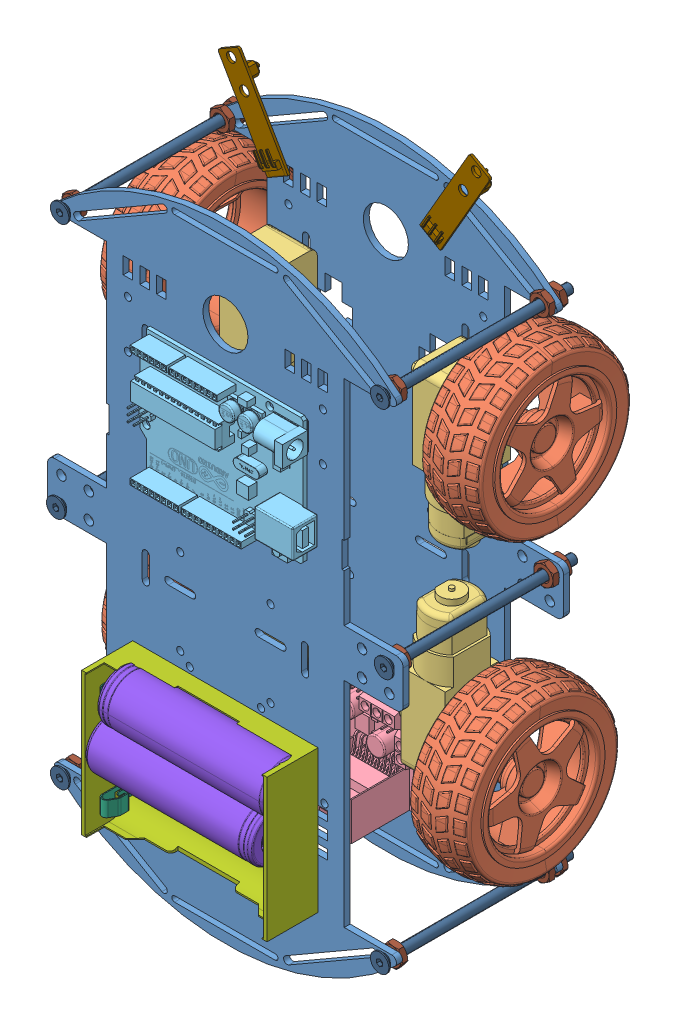
SolidWorks assembly Assem1, configuration Default. Lengths in mm.
Overall size (160.5 272.74 118.28).
52 component instances, 11 part files, 84 mates.
Components (placement in the parent):
- Chassis-1: Chassis [Défaut] at (34.1523 63.1715 225.3046) size (149.66 262 2.5)
- ensemble roue-1: ensemble roue [Default] at (48.6677 124.5638 247.2809) x (0 0.999098 -0.042468) z (-1 0 0) size (89.53 69.08 58.2)
  - Wheel D65x25-1: Wheel D65x25 [Default] at (-64.7956 10.9879 41.7655) size (69.1 69.08 30)
  - Arduino Gear Motor-1: Arduino Gear Motor [Default] at (-75.7856 11.455 2.1655) x (0 0 1) z (-0.999098 0.042468 0) size (37.2 22.5 65.5)
- ensemble roue-2: ensemble roue [Default] at (120.1368 124.5638 230.8284) x (0 0.999098 0.042468) z (1 0 0) size (89.53 69.08 58.2)
  - Wheel D65x25-1: Wheel D65x25 [Default] at (-64.7956 10.9879 41.7655) size (69.1 69.08 30)
  - Arduino Gear Motor-1: Arduino Gear Motor [Default] at (-75.7856 11.455 2.1655) x (0 0 1) z (-0.999098 0.042468 0) size (37.2 22.5 65.5)
- ensemble roue-4: ensemble roue [Default] at (48.1677 122.1564 230.8284) x (0 -0.999098 0.042468) z (-1 0 0) size (89.53 69.08 58.2)
  - Wheel D65x25-1: Wheel D65x25 [Default] at (-64.7956 10.9879 41.7655) size (69.1 69.08 30)
  - Arduino Gear Motor-1: Arduino Gear Motor [Default] at (-75.7856 11.455 2.1655) x (0 0 1) z (-0.999098 0.042468 0) size (37.2 22.5 65.5)
- ensemble roue-5: ensemble roue [Default] at (125.1368 122.1564 247.2809) x (0 -0.999098 -0.042468) z (1 0 0) size (89.53 69.08 58.2)
  - Wheel D65x25-1: Wheel D65x25 [Default] at (-64.7956 10.9879 41.7655) size (69.1 69.08 30)
  - Arduino Gear Motor-1: Arduino Gear Motor [Default] at (-75.7856 11.455 2.1655) x (0 0 1) z (-0.999098 0.042468 0) size (37.2 22.5 65.5)
- L298N Motor Driver-1: L298N Motor Driver [Default] at (84.1523 35.5001 227.8046) x (1 0 0) z (0 -1 0) size (43.5 26 43.5)
- Chassis-2: Chassis [Défaut] at (34.1523 63.1715 292.8046) size (149.66 262 2.5)
- Arduino UNO-1: Arduino UNO [Predeterminado] at (82.8616 175.6554 295.3046) x (-1 0 0) z (0 1 0) size (74.8 15.1 53.3)
- Hold_18650-3p.stp-1: Hold_18650-3p.stp [Default] at (84.1523 53.3601 295.3046) x (0 -1 0) z (0 0 1) size (60 78 25.5)
  - eBom-prt0.stp-1: eBom-prt0.stp [Default] at (-20 -36 0) size (6.4 5.3 21.4)
  - eBom-prt0.stp-2: eBom-prt0.stp [Default] at (-20 36 0) x (-1 0 0) z (0 0 1) size (6.4 5.3 21.4)
  - eBom-prt0.stp-3: eBom-prt0.stp [Default] at (0 -36 0) size (6.4 5.3 21.4)
  - eBom-prt0.stp-4: eBom-prt0.stp [Default] at (0 36 0) x (-1 0 0) z (0 0 1) size (6.4 5.3 21.4)
  - eBom-prt0.stp-5: eBom-prt0.stp [Default] at (20 -36 0) size (6.4 5.3 21.4)
  - eBom-prt0.stp-6: eBom-prt0.stp [Default] at (20 36 0) x (-1 0 0) z (0 0 1) size (6.4 5.3 21.4)
  - eBom-prt1.stp-1: eBom-prt1.stp [Default] at origin size (60 78 21.5)
- 21700_li_battery-1: 21700_li_battery [Default] at (121.6523 73.3601 306.8046) x (0 1 0) z (0 0 1) size (21 70.03 21)
- 21700_li_battery-2: 21700_li_battery [Default] at (46.6523 53.3601 306.8046) x (0 0.381849 -0.924225) z (0 -0.924225 -0.381849) size (21 70.03 21)
- Sensor-1: Sensor [Default] at (113.9417 243.9854 228.8046) x (0.5 0.866025 0) z (-0.866025 0.5 0) size (42 9.8 10)
- Sensor-2: Sensor [Default] at (29.3788 234.1797 228.8046) x (-0.5 0.866025 0) z (-0.866025 -0.5 0) size (42 9.8 10)
- socket countersunk head screw_am-14: socket countersunk head screw_am [B18.3.5M - 4 x 0.7 x 55 Socket FCHS  -- 20N] at (151.4798 226.3601 297.7261) x (0 0 -1) z (-0.801739 -0.597675 0) size (80 7.8 7.8)
- socket countersunk head screw_am-15: socket countersunk head screw_am [B18.3.5M - 4 x 0.7 x 55 Socket FCHS  -- 20N] at (16.8248 226.3601 297.7261) x (0 0 -1) z (1 0 0) size (80 7.8 7.8)
- socket countersunk head screw_am-16: socket countersunk head screw_am [B18.3.5M - 4 x 0.7 x 55 Socket FCHS  -- 20N] at (153.1319 128.6487 297.7261) x (0 0 -1) z (1 0 0) size (80 7.8 7.8)
- socket countersunk head screw_am-13: socket countersunk head screw_am [B18.3.5M - 4 x 0.7 x 55 Socket FCHS  -- 20N] at (151.4798 20.3601 297.7261) x (0 0 -1) z (1 0 0) size (80 7.8 7.8)
- socket countersunk head screw_am-17: socket countersunk head screw_am [B18.3.5M - 4 x 0.7 x 55 Socket FCHS  -- 20N] at (16.8248 20.3601 297.7261) x (0 0 -1) z (1 0 0) size (80 7.8 7.8)
- socket countersunk head screw_am-12: socket countersunk head screw_am [B18.3.5M - 4 x 0.7 x 55 Socket FCHS  -- 20N] at (15.1726 118.0715 297.7261) x (0 0 -1) z (1 0 0) size (80 7.8 7.8)
- hex nut jam_am-1: hex nut jam_am [B18.2.4.5M - Hex jam nut,  M5 x 0.8 --D-N] at (151.4798 226.3601 292.8046) size (8 9.24 2.7)
- hex nut jam_am-2: hex nut jam_am [B18.2.4.5M - Hex jam nut,  M5 x 0.8 --D-N] at (151.4798 226.3601 230.5046) size (8 9.24 2.7)
- hex nut jam_am-3: hex nut jam_am [B18.2.4.5M - Hex jam nut,  M5 x 0.8 --D-N] at (151.4798 226.3601 222.6046) x (0.923728 0.383049 0) z (0 0 -1) size (8 9.24 2.7)
- hex nut jam_am-4: hex nut jam_am [B18.2.4.5M - Hex jam nut,  M5 x 0.8 --D-N] at (153.1319 128.6487 290.1046) x (0.923728 0.383049 0) z (0 0 -1) size (8 9.24 2.7)
- hex nut jam_am-5: hex nut jam_am [B18.2.4.5M - Hex jam nut,  M5 x 0.8 --D-N] at (151.4798 20.3601 290.1046) x (0.923728 0.383049 0) z (0 0 -1) size (8 9.24 2.7)
- hex nut jam_am-6: hex nut jam_am [B18.2.4.5M - Hex jam nut,  M5 x 0.8 --D-N] at (16.8248 20.3601 290.1046) x (0.923728 0.383049 0) z (0 0 -1) size (8 9.24 2.7)
- hex nut jam_am-7: hex nut jam_am [B18.2.4.5M - Hex jam nut,  M5 x 0.8 --D-N] at (15.1726 118.0715 290.1046) x (0.923728 0.383049 0) z (0 0 -1) size (8 9.24 2.7)
- hex nut jam_am-8: hex nut jam_am [B18.2.4.5M - Hex jam nut,  M5 x 0.8 --D-N] at (16.8248 226.3601 292.8046) x (0.999998 0.001761 0) z (0 0 1) size (8 9.24 2.7)
- hex nut jam_am-9: hex nut jam_am [B18.2.4.5M - Hex jam nut,  M5 x 0.8 --D-N] at (16.8248 226.3601 230.5046) size (8 9.24 2.7)
- hex nut jam_am-10: hex nut jam_am [B18.2.4.5M - Hex jam nut,  M5 x 0.8 --D-N] at (15.1726 118.0715 230.5046) size (8 9.24 2.7)
- hex nut jam_am-11: hex nut jam_am [B18.2.4.5M - Hex jam nut,  M5 x 0.8 --D-N] at (16.8248 20.3601 230.5046) size (8 9.24 2.7)
- hex nut jam_am-12: hex nut jam_am [B18.2.4.5M - Hex jam nut,  M5 x 0.8 --D-N] at (16.8248 20.3601 222.6046) x (0.923728 0.383049 0) z (0 0 -1) size (8 9.24 2.7)
- hex nut jam_am-13: hex nut jam_am [B18.2.4.5M - Hex jam nut,  M5 x 0.8 --D-N] at (15.1726 118.0715 222.6046) x (0.923728 0.383049 0) z (0 0 -1) size (8 9.24 2.7)
- hex nut jam_am-14: hex nut jam_am [B18.2.4.5M - Hex jam nut,  M5 x 0.8 --D-N] at (16.8248 226.3601 222.6046) x (0.923728 0.383049 0) z (0 0 -1) size (8 9.24 2.7)
- hex nut jam_am-15: hex nut jam_am [B18.2.4.5M - Hex jam nut,  M5 x 0.8 --D-N] at (153.1319 128.6487 222.6046) x (0.923728 0.383049 0) z (0 0 -1) size (8 9.24 2.7)
- hex nut jam_am-16: hex nut jam_am [B18.2.4.5M - Hex jam nut,  M5 x 0.8 --D-N] at (151.4798 20.3601 222.6046) x (0.923728 0.383049 0) z (0 0 -1) size (8 9.24 2.7)
- hex nut jam_am-17: hex nut jam_am [B18.2.4.5M - Hex jam nut,  M5 x 0.8 --D-N] at (151.4798 20.3601 230.5046) size (8 9.24 2.7)
- hex nut jam_am-18: hex nut jam_am [B18.2.4.5M - Hex jam nut,  M5 x 0.8 --D-N] at (153.1319 128.6487 230.5046) size (8 9.24 2.7)
Mates (geometry in assembly coordinates):
- Coincident1: coincident anti-aligned: plane of Chassis-1 through (154.1465 21.3601 227.8046) normal (0 0 1); plane of ensemble roue-1/Arduino Gear Motor-1 through (55.8523 48.3601 227.8046) normal (0 0 -1)
- Parallel1: parallel anti-aligned: plane of Chassis-1 through (34.1523 23.3601 227.8046) normal (-1 0 0); plane of ensemble roue-1/Arduino Gear Motor-1 through (55.8523 48.3601 250.3046) normal (1 0 0)
- Distance1: distance = 3 mm aligned: plane of ensemble roue-1/Arduino Gear Motor-1 through (37.1523 48.3601 227.8046) normal (-1 0 0); plane of Chassis-1 through (34.1523 23.3601 227.8046) normal (-1 0 0)
- Distance5: distance = 25 mm anti-aligned: plane of ensemble roue-1/Arduino Gear Motor-1 through (46.5023 48.3601 239.0546) normal (0 -1 0); plane of Chassis-1 through (34.1523 23.3601 227.8046) normal (0 1 0)
- Coincident6: coincident anti-aligned: plane of Chassis-1 through (154.1465 21.3601 227.8046) normal (0 0 1); plane of ensemble roue-4/Arduino Gear Motor-1 through (36.6523 198.3601 227.8046) normal (0 0 -1)
- Distance3: distance = 2.5 mm aligned: plane of ensemble roue-4/Arduino Gear Motor-1 through (36.6523 198.3601 250.3046) normal (-1 0 0); plane of Chassis-1 through (34.1523 133.3601 227.8046) normal (-1 0 0)
- Distance4: distance = 25 mm anti-aligned: plane of ensemble roue-4/Arduino Gear Motor-1 through (46.0023 198.3601 239.0546) normal (0 1 0); plane of Chassis-1 through (34.1523 223.3601 227.8046) normal (0 -1 0)
- Coincident9: coincident anti-aligned: plane of Chassis-1 through (154.1465 21.3601 227.8046) normal (0 0 1); plane of ensemble roue-2/Arduino Gear Motor-1 through (131.6523 48.3601 227.8046) normal (0 0 -1)
- Distance7: distance = 2.5 mm aligned: plane of Chassis-1 through (134.1523 23.3601 227.8046) normal (1 0 0); plane of ensemble roue-2/Arduino Gear Motor-1 through (131.6523 48.3601 250.3046) normal (1 0 0)
- Distance6: distance = 25 mm anti-aligned: plane of ensemble roue-2/Arduino Gear Motor-1 through (122.3023 48.3601 239.0546) normal (0 -1 0); plane of Chassis-1 through (134.1523 23.3601 227.8046) normal (0 1 0)
- Coincident13: coincident anti-aligned: plane of Chassis-1 through (154.1465 21.3601 227.8046) normal (0 0 1); plane of ensemble roue-5/Arduino Gear Motor-1 through (117.9523 198.3601 227.8046) normal (0 0 -1)
- Distance8: distance = 2.5 mm aligned: plane of ensemble roue-5/Arduino Gear Motor-1 through (136.6523 198.3601 227.8046) normal (1 0 0); plane of Chassis-1 through (134.1523 133.3601 227.8046) normal (1 0 0)
- Distance9: distance = 25 mm anti-aligned: plane of ensemble roue-5/Arduino Gear Motor-1 through (127.3023 198.3601 239.0546) normal (0 1 0); plane of Chassis-1 through (134.1523 223.3601 227.8046) normal (0 -1 0)
- Coincident16: coincident anti-aligned: plane of Chassis-1 through (154.1465 21.3601 227.8046) normal (0 0 1); plane of L298N Motor Driver-1 through (84.1523 35.5001 227.8046) normal (0 0 -1)
- Width1: width anti-aligned: plane of L298N Motor Driver-1 through (62.4023 13.7501 229.3046) normal (-1 0 0); plane of L298N Motor Driver-1 through (105.9023 13.7501 229.3046) normal (1 0 0); plane of Chassis-1 through (134.1523 23.3601 227.8046) normal (1 0 0); plane of Chassis-1 through (34.1523 23.3601 227.8046) normal (-1 0 0)
- Distance10: distance = 56.11 mm anti-aligned: plane of Chassis-1 through (34.1523 113.3601 227.8046) normal (0 -1 0); plane of L298N Motor Driver-1 through (62.4023 57.2501 229.3046) normal (0 1 0)
- Concentric1: concentric aligned: cylinder of Chassis-1 through (15.1726 118.0715 225.3046) axis (0 0 1) radius 2; cylinder of Chassis-2 through (15.1726 118.0715 292.8046) axis (0 0 1) radius 2
- Concentric2: concentric aligned: cylinder of Chassis-1 through (153.1319 128.6487 225.3046) axis (0 0 1) radius 2; cylinder of Chassis-2 through (153.1319 128.6487 292.8046) axis (0 0 1) radius 2
- Distance11: distance = 65 mm anti-aligned: plane of Chassis-1 through (154.1465 21.3601 227.8046) normal (0 0 1); plane of Chassis-2 through (154.1465 21.3601 292.8046) normal (0 0 -1)
- Coincident19: coincident anti-aligned: plane of Chassis-2 through (154.1465 21.3601 295.3046) normal (0 0 1); plane of Arduino UNO-1 through (82.8616 175.6554 295.3046) normal (0 0 -1)
- Width2: width aligned: plane of Arduino UNO-1 through (49.8523 164.0601 296.9046) normal (-1 0 0); plane of Arduino UNO-1 through (118.4523 200.6601 296.9046) normal (1 0 0); plane of Chassis-2 through (34.1523 133.3601 295.3046) normal (-1 0 0); plane of Chassis-2 through (134.1523 133.3601 295.3046) normal (1 0 0)
- Distance12: distance = 15 mm anti-aligned: plane of Arduino UNO-1 through (53.4523 148.3601 296.9046) normal (0 -1 0); plane of Chassis-2 through (134.1523 133.3601 295.3046) normal (0 1 0)
- Coincident21: coincident anti-aligned: plane of Chassis-2 through (154.1465 21.3601 295.3046) normal (0 0 1); plane of Hold_18650-3p.stp-1/eBom-prt1.stp-1 through (84.1523 53.3601 295.3046) normal (0 0 -1)
- Distance13: distance = 30 mm anti-aligned: plane of Hold_18650-3p.stp-1/eBom-prt1.stp-1 through (123.1523 83.3601 295.3046) normal (0 1 0); plane of Chassis-2 through (34.1523 113.3601 295.3046) normal (0 -1 0)
- Width3: width anti-aligned: plane of Hold_18650-3p.stp-1/eBom-prt1.stp-1 through (45.1523 83.3601 295.3046) normal (-1 0 0); plane of Hold_18650-3p.stp-1/eBom-prt1.stp-1 through (123.1523 23.3601 295.3046) normal (1 0 0); plane of Chassis-2 through (134.1523 23.3601 295.3046) normal (1 0 0); plane of Chassis-2 through (34.1523 23.3601 295.3046) normal (-1 0 0)
- Coincident23: coincident anti-aligned: plane of Hold_18650-3p.stp-1/eBom-prt1.stp-1 through (121.6523 53.3601 295.3046) normal (-1 0 0); plane of 21700_li_battery-1 through (121.6523 73.3601 306.8046) normal (1 0 0)
- Concentric3: concentric aligned: cylinder of Hold_18650-3p.stp-1/eBom-prt1.stp-1 through (46.6523 73.3601 306.8046) axis (1 0 0) radius 9.5; cylinder of 21700_li_battery-1 through (51.6523 73.3601 306.8046) axis (1 0 0) radius 10.5
- Coincident24: coincident anti-aligned: plane of Hold_18650-3p.stp-1/eBom-prt1.stp-1 through (46.6523 53.3601 295.3046) normal (1 0 0); plane of 21700_li_battery-2 through (46.6523 53.3601 306.8046) normal (-1 0 0)
- Concentric4: concentric anti-aligned: cylinder of Hold_18650-3p.stp-1/eBom-prt1.stp-1 through (46.6523 53.3601 306.8046) axis (1 0 0) radius 9.5; cylinder of 21700_li_battery-2 through (116.6523 53.3601 306.8046) axis (-1 0 0) radius 10.5
- Coincident26: coincident anti-aligned: plane of Chassis-1 through (154.1465 21.3601 227.8046) normal (0 0 1); plane of Sensor-1 through (113.9417 243.9854 227.8046) normal (0 0 -1)
- Parallel3: parallel aligned: plane of Chassis-1 through (145.7396 225.0611 227.8046) normal (0.5 0.866025 0); plane of Sensor-1 through (124.6917 262.605 227.8046) normal (0.5 0.866025 0)
- Distance15: distance = 11 mm anti-aligned: plane of Sensor-1 through (123.5181 250.5924 223.8046) normal (-0.5 -0.866025 0); plane of Chassis-1 through (145.7396 225.0611 227.8046) normal (0.5 0.866025 0)
- Coincident29: coincident: point of Chassis-1; plane of Sensor-1 through (109.6116 246.4854 227.8046) normal (-0.866025 0.5 0)
- Coincident30: coincident anti-aligned: plane of Chassis-1 through (154.1465 21.3601 227.8046) normal (0 0 1); plane of Sensor-2 through (29.3788 234.1797 227.8046) normal (0 0 -1)
- Parallel5: parallel anti-aligned: plane of Chassis-1 through (22.5649 225.0611 227.8046) normal (-0.5 0.866025 0); plane of Sensor-2 through (39.6288 216.4262 227.8046) normal (0.5 -0.866025 0)
- Distance16: distance = 15 mm anti-aligned: plane of Chassis-1 through (22.5649 225.0611 227.8046) normal (-0.5 0.866025 0); plane of Sensor-2 through (28.4453 245.7766 223.8046) normal (0.5 -0.866025 0)
- Concentric13: concentric aligned: cylinder of Chassis-2 through (151.4798 226.3601 295.3046) axis (0 0 -1) radius 2; cone of socket countersunk head screw_am-6 through (151.4798 226.3601 297.1461) axis (0 0 -1)
- Coincident38: coincident aligned: plane of Chassis-2 through (154.1465 21.3601 295.3046) normal (0 0 1); circle of socket countersunk head screw_am-6
- Concentric14: concentric anti-aligned: cylinder of Chassis-2 through (16.8248 226.3601 295.3046) axis (0 0 -1) radius 2; cylinder of socket countersunk head screw_am-7 through (16.8248 226.3601 297.7261) axis (0 0 1) radius 2
- Coincident39: coincident aligned: plane of Chassis-2 through (154.1465 21.3601 295.3046) normal (0 0 1); circle of socket countersunk head screw_am-7
- Concentric16: concentric aligned: cylinder of Chassis-2 through (15.1726 118.0715 292.8046) axis (0 0 1) radius 2; cylinder of socket countersunk head screw_am-12 through (15.1726 118.0715 297.7261) axis (0 0 1) radius 2
- Concentric17: concentric anti-aligned: cylinder of Chassis-2 through (16.8248 20.3601 295.3046) axis (0 0 -1) radius 2; cylinder of socket countersunk head screw_am-10 through (16.8248 20.3601 297.7261) axis (0 0 1) radius 2
- Concentric18: concentric anti-aligned: cylinder of Chassis-2 through (151.4798 20.3601 295.3046) axis (0 0 -1) radius 2; cylinder of socket countersunk head screw_am-9 through (151.4798 20.3601 297.7261) axis (0 0 1) radius 2
- Concentric19: concentric aligned: cylinder of Chassis-2 through (153.1319 128.6487 292.8046) axis (0 0 1) radius 2; cylinder of socket countersunk head screw_am-8 through (153.1319 128.6487 297.7261) axis (0 0 1) radius 2
- Coincident40: coincident aligned: plane of Chassis-2 through (154.1465 21.3601 295.3046) normal (0 0 1); circle of socket countersunk head screw_am-8
- Coincident41: coincident aligned: plane of Chassis-2 through (154.1465 21.3601 295.3046) normal (0 0 1); circle of socket countersunk head screw_am-9
- Coincident42: coincident aligned: plane of Chassis-2 through (154.1465 21.3601 295.3046) normal (0 0 1); circle of socket countersunk head screw_am-10
- Coincident43: coincident aligned: plane of Chassis-2 through (154.1465 21.3601 295.3046) normal (0 0 1); circle of socket countersunk head screw_am-12
- Concentric22: concentric aligned: cylinder of socket countersunk head screw_am-6 through (151.4798 226.3601 297.7261) axis (0 0 1) radius 2; cylinder of hex nut jam_am-1 through (151.4798 226.3601 267.7671) axis (0 0 1) radius 2.5
- Concentric23: concentric anti-aligned: cylinder of Chassis-1 through (151.4798 226.3601 227.8046) axis (0 0 -1) radius 2; cylinder of hex nut jam_am-2 through (151.4798 226.3601 205.4671) axis (0 0 1) radius 2.5
- Coincident44: coincident anti-aligned: plane of Chassis-1 through (154.1465 21.3601 227.8046) normal (0 0 1); plane of hex nut jam_am-2 through (151.4798 230.9789 227.8046) normal (0 0 -1)
- Concentric24: concentric aligned: cylinder of Chassis-1 through (151.4798 226.3601 227.8046) axis (0 0 -1) radius 2; cylinder of hex nut jam_am-3 through (151.4798 226.3601 247.6421) axis (0 0 -1) radius 2.5
- Coincident45: coincident anti-aligned: plane of Chassis-1 through (154.1465 21.3601 225.3046) normal (0 0 -1); plane of hex nut jam_am-3 through (153.249 222.0936 225.3046) normal (0 0 1)
- Concentric25: concentric anti-aligned: cylinder of socket countersunk head screw_am-8 through (153.1319 128.6487 297.7261) axis (0 0 1) radius 2; cylinder of hex nut jam_am-4 through (153.1319 128.6487 315.1421) axis (0 0 -1) radius 2.5
- Coincident46: coincident anti-aligned: plane of Chassis-2 through (154.1465 21.3601 292.8046) normal (0 0 -1); plane of hex nut jam_am-4 through (154.9011 124.3822 292.8046) normal (0 0 1)
- Concentric26: concentric anti-aligned: cylinder of socket countersunk head screw_am-9 through (151.4798 20.3601 297.7261) axis (0 0 1) radius 2; cylinder of hex nut jam_am-5 through (151.4798 20.3601 315.1421) axis (0 0 -1) radius 2.5
- Coincident47: coincident anti-aligned: plane of Chassis-2 through (154.1465 21.3601 292.8046) normal (0 0 -1); plane of hex nut jam_am-5 through (153.249 16.0936 292.8046) normal (0 0 1)
- Concentric27: concentric anti-aligned: cylinder of socket countersunk head screw_am-10 through (16.8248 20.3601 297.7261) axis (0 0 1) radius 2; cylinder of hex nut jam_am-6 through (16.8248 20.3601 315.1421) axis (0 0 -1) radius 2.5
- Coincident48: coincident anti-aligned: plane of Chassis-2 through (154.1465 21.3601 292.8046) normal (0 0 -1); plane of hex nut jam_am-6 through (18.594 16.0936 292.8046) normal (0 0 1)
- Concentric28: concentric anti-aligned: cylinder of socket countersunk head screw_am-12 through (15.1726 118.0715 297.7261) axis (0 0 1) radius 2; cylinder of hex nut jam_am-7 through (15.1726 118.0715 315.1421) axis (0 0 -1) radius 2.5
- Coincident49: coincident anti-aligned: plane of Chassis-2 through (154.1465 21.3601 292.8046) normal (0 0 -1); plane of hex nut jam_am-7 through (16.9419 113.805 292.8046) normal (0 0 1)
- Concentric29: concentric aligned: cylinder of socket countersunk head screw_am-7 through (16.8248 226.3601 297.7261) axis (0 0 1) radius 2; cylinder of hex nut jam_am-8 through (16.8248 226.3601 267.7671) axis (0 0 1) radius 2.5
- Concentric30: concentric aligned: cylinder of socket countersunk head screw_am-7 through (16.8248 226.3601 297.7261) axis (0 0 1) radius 2; cylinder of hex nut jam_am-9 through (16.8248 226.3601 205.4671) axis (0 0 1) radius 2.5
- Coincident50: coincident anti-aligned: plane of Chassis-1 through (154.1465 21.3601 227.8046) normal (0 0 1); plane of hex nut jam_am-9 through (16.8248 230.9789 227.8046) normal (0 0 -1)
- Concentric31: concentric aligned: cylinder of socket countersunk head screw_am-12 through (15.1726 118.0715 297.7261) axis (0 0 1) radius 2; cylinder of hex nut jam_am-10 through (15.1726 118.0715 205.4671) axis (0 0 1) radius 2.5
- Coincident51: coincident anti-aligned: plane of Chassis-1 through (154.1465 21.3601 227.8046) normal (0 0 1); plane of hex nut jam_am-10 through (15.1726 122.6903 227.8046) normal (0 0 -1)
- Concentric32: concentric aligned: cylinder of socket countersunk head screw_am-10 through (16.8248 20.3601 297.7261) axis (0 0 1) radius 2; cylinder of hex nut jam_am-11 through (16.8248 20.3601 205.4671) axis (0 0 1) radius 2.5
- Coincident52: coincident anti-aligned: plane of Chassis-1 through (154.1465 21.3601 227.8046) normal (0 0 1); plane of hex nut jam_am-11 through (16.8248 24.9789 227.8046) normal (0 0 -1)
- Concentric33: concentric anti-aligned: cylinder of socket countersunk head screw_am-10 through (16.8248 20.3601 297.7261) axis (0 0 1) radius 2; cylinder of hex nut jam_am-12 through (16.8248 20.3601 247.6421) axis (0 0 -1) radius 2.5
- Coincident53: coincident anti-aligned: plane of Chassis-1 through (154.1465 21.3601 225.3046) normal (0 0 -1); plane of hex nut jam_am-12 through (18.594 16.0936 225.3046) normal (0 0 1)
- Concentric34: concentric anti-aligned: cylinder of socket countersunk head screw_am-12 through (15.1726 118.0715 297.7261) axis (0 0 1) radius 2; cylinder of hex nut jam_am-13 through (15.1726 118.0715 247.6421) axis (0 0 -1) radius 2.5
- Coincident54: coincident anti-aligned: plane of Chassis-1 through (154.1465 21.3601 225.3046) normal (0 0 -1); plane of hex nut jam_am-13 through (16.9419 113.805 225.3046) normal (0 0 1)
- Concentric35: concentric anti-aligned: cylinder of socket countersunk head screw_am-7 through (16.8248 226.3601 297.7261) axis (0 0 1) radius 2; cylinder of hex nut jam_am-14 through (16.8248 226.3601 247.6421) axis (0 0 -1) radius 2.5
- Coincident55: coincident anti-aligned: plane of Chassis-1 through (154.1465 21.3601 225.3046) normal (0 0 -1); plane of hex nut jam_am-14 through (18.594 222.0936 225.3046) normal (0 0 1)
- Concentric36: concentric anti-aligned: cylinder of socket countersunk head screw_am-8 through (153.1319 128.6487 297.7261) axis (0 0 1) radius 2; cylinder of hex nut jam_am-15 through (153.1319 128.6487 247.6421) axis (0 0 -1) radius 2.5
- Coincident56: coincident anti-aligned: plane of Chassis-1 through (154.1465 21.3601 225.3046) normal (0 0 -1); plane of hex nut jam_am-15 through (154.9011 124.3822 225.3046) normal (0 0 1)
- Concentric37: concentric anti-aligned: cylinder of socket countersunk head screw_am-9 through (151.4798 20.3601 297.7261) axis (0 0 1) radius 2; cylinder of hex nut jam_am-16 through (151.4798 20.3601 247.6421) axis (0 0 -1) radius 2.5
- Coincident57: coincident anti-aligned: plane of Chassis-1 through (154.1465 21.3601 225.3046) normal (0 0 -1); plane of hex nut jam_am-16 through (153.249 16.0936 225.3046) normal (0 0 1)
- Concentric38: concentric aligned: cylinder of socket countersunk head screw_am-9 through (151.4798 20.3601 297.7261) axis (0 0 1) radius 2; cylinder of hex nut jam_am-17 through (151.4798 20.3601 205.4671) axis (0 0 1) radius 2.5
- Coincident58: coincident anti-aligned: plane of Chassis-1 through (154.1465 21.3601 227.8046) normal (0 0 1); plane of hex nut jam_am-17 through (151.4798 24.9789 227.8046) normal (0 0 -1)
- Concentric39: concentric aligned: cylinder of socket countersunk head screw_am-8 through (153.1319 128.6487 297.7261) axis (0 0 1) radius 2; cylinder of hex nut jam_am-18 through (153.1319 128.6487 205.4671) axis (0 0 1) radius 2.5
- Coincident59: coincident anti-aligned: plane of Chassis-1 through (154.1465 21.3601 227.8046) normal (0 0 1); plane of hex nut jam_am-18 through (153.1319 133.2676 227.8046) normal (0 0 -1)
- Coincident60: coincident anti-aligned: plane of Chassis-2 through (154.1465 21.3601 292.8046) normal (0 0 -1); plane of hex nut jam_am-1 through (151.4798 230.9789 292.8046) normal (0 0 1)
- Coincident61: coincident anti-aligned: plane of Chassis-2 through (154.1465 21.3601 292.8046) normal (0 0 -1); plane of hex nut jam_am-8 through (16.8166 230.9789 292.8046) normal (0 0 1)
